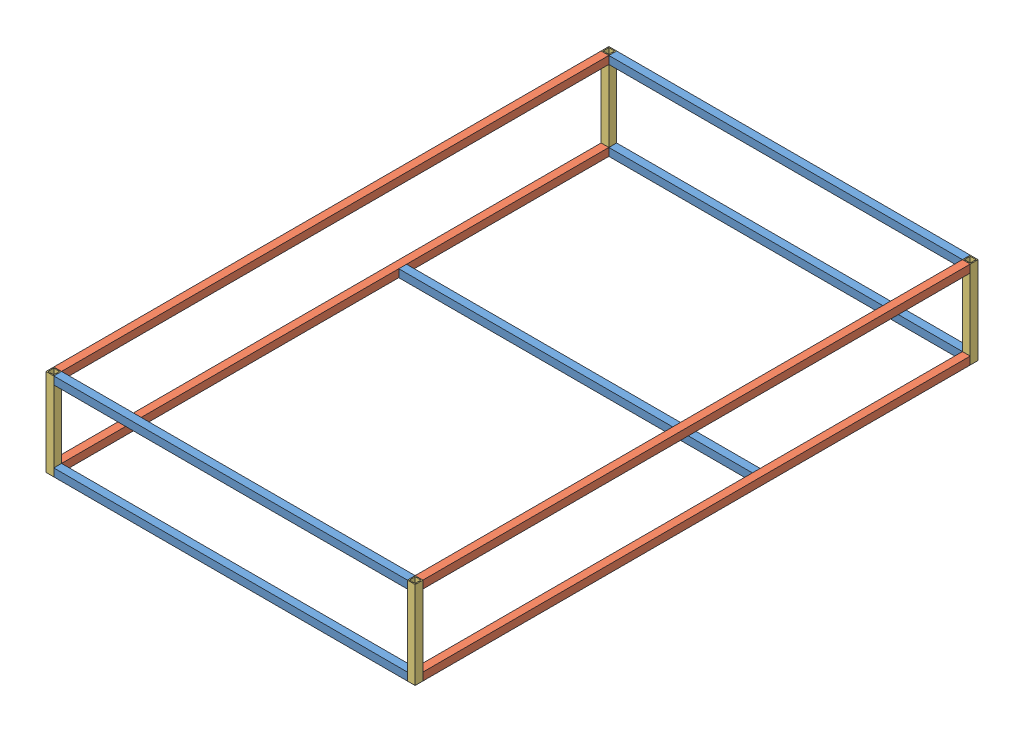
SolidWorks assembly Frame (Base), configuration Default. Lengths in mm.
Overall size (1900 450 2897).
13 component instances, 3 part files, 31 mates.
Components (placement in the parent):
- Frame 1820 steel extrusion-8: Frame 1820 steel extrusion [Default] at origin size (1820 40 40)
- Frame 1820 steel extrusion-9: Frame 1820 steel extrusion [Default] at (0 0 -1775.6695) x (1 0 0) z (0 1 0) size (1820 40 40)
- Frame 1820 steel extrusion-10: Frame 1820 steel extrusion [Default] at (0 410 0) size (1820 40 40)
- Frame 1820 steel extrusion-12: Frame 1820 steel extrusion [Default] at (0 0 -2857) x (1 0 0) z (0 0 -1) size (1820 40 40)
- Frame 1820 steel extrusion-13: Frame 1820 steel extrusion [Default] at (0 410 -2857) x (1 0 0) z (0 1 0) size (1820 40 40)
- Frame 2857 steel extrusion-1: Frame 2857 steel extrusion [Default] at (930 0 -1428.5) x (0 1 0) z (-1 0 0) size (40 2817 40)
- Frame 2857 steel extrusion-2: Frame 2857 steel extrusion [Default] at (930 410 -1428.5) x (0 1 0) z (-1 0 0) size (40 2817 40)
- Frame 2857 steel extrusion-3: Frame 2857 steel extrusion [Default] at (-930 410 -1428.5) x (0 1 0) z (-1 0 0) size (40 2817 40)
- Frame 2857 steel extrusion-4: Frame 2857 steel extrusion [Default] at (-930 0 -1428.5) x (0 1 0) z (-1 0 0) size (40 2817 40)
- Frame 450 steel extrusion-1: Frame 450 steel extrusion [Default] at (-930 205 0) x (0 0 -1) z (-1 0 0) size (40 450 40)
- Frame 450 steel extrusion-2: Frame 450 steel extrusion [Default] at (930 205 0) x (0 0 -1) z (-1 0 0) size (40 450 40)
- Frame 450 steel extrusion-3: Frame 450 steel extrusion [Default] at (930 205 -2857) x (0 0 -1) z (-1 0 0) size (40 450 40)
- Frame 450 steel extrusion-4: Frame 450 steel extrusion [Default] at (-930 205 -2857) x (1 0 0) z (0 0 -1) size (40 450 40)
Mates (geometry in assembly coordinates):
- Coincidente129: coincident: line of assembly; line of assembly; line of Frame 2857 steel extrusion-1 through (910 -20 -20) axis (0 1 0); line of Frame 450 steel extrusion-2 through (910 -20 -20) axis (0 1 0)
- Coincidente130: coincident: line of assembly; line of assembly; line of Frame 2857 steel extrusion-1 through (950 -20 -20) axis (-1 0 0); line of Frame 450 steel extrusion-2 through (910 -20 -20) axis (1 0 0)
- Coincidente133: coincident: line of assembly; line of assembly; line of Frame 2857 steel extrusion-1 through (910 20 -2837) axis (0 0 1); line of Frame 1820 steel extrusion-9 through (910 20 -1795.6695) axis (0 0 1)
- Coincidente171: coincident: line of assembly; line of assembly; line of Frame 2857 steel extrusion-1 through (950 20 -2837) axis (0 -1 0); line of Frame 450 steel extrusion-3 through (950 -20 -2837) axis (0 1 0)
- Coincidente116: coincident: line of assembly; line of assembly; line of Frame 450 steel extrusion-1 through (-910 -20 20) axis (0 1 0); line of Frame 1820 steel extrusion-10 through (-910 430 20) axis (0 -1 0)
- Coincidente117: coincident: line of assembly; line of assembly; line of Frame 450 steel extrusion-1 through (-910 430 20) axis (-1 0 0); line of Frame 1820 steel extrusion-10 through (910 430 20) axis (-1 0 0)
- Coincidente139: coincident: line of assembly; line of assembly; line of Frame 450 steel extrusion-1 through (-950 -20 -20) axis (0 1 0); line of Frame 2857 steel extrusion-3 through (-950 390 -20) axis (0 1 0)
- Coincidente140: coincident: line of assembly; line of assembly; line of Frame 450 steel extrusion-1 through (-950 430 -20) axis (1 0 0); line of Frame 2857 steel extrusion-3 through (-950 430 -20) axis (1 0 0)
- Coincidente180: coincident: line of assembly; line of assembly; line of Frame 450 steel extrusion-1 through (-950 -20 -20) axis (1 0 0); line of Frame 2857 steel extrusion-4 through (-910 -20 -20) axis (-1 0 0)
- Coincidente127: coincident: plane of assembly; plane of assembly; plane of Frame 450 steel extrusion-2 through (950 -20 -20) normal (1 0 0); plane of Frame 450 steel extrusion-3 through (950 -20 -2877) normal (1 0 0)
- Coincidente137: coincident: line of assembly; line of assembly; line of Frame 450 steel extrusion-2 through (950 -20 -20) axis (0 1 0); line of Frame 2857 steel extrusion-2 through (950 430 -20) axis (0 -1 0)
- Coincidente138: coincident: line of assembly; line of assembly; line of Frame 450 steel extrusion-2 through (910 430 -20) axis (1 0 0); line of Frame 2857 steel extrusion-2 through (910 430 -20) axis (1 0 0)
- Coincident15: coincident: plane of assembly; plane of assembly; plane of Frame 450 steel extrusion-3 through (910 -20 -2877) normal (-1 0 0); plane of Frame 1820 steel extrusion-13 through (910 410 -2857) normal (1 0 0)
- Coincident16: coincident: plane of assembly; plane of assembly; plane of Frame 450 steel extrusion-3 through (930 430 -2857) normal (0 1 0); plane of Frame 1820 steel extrusion-13 through (910 430 -2837) normal (0 1 0)
- Coincident17: coincident: plane of assembly; plane of assembly; plane of Frame 450 steel extrusion-3 through (910 -20 -2837) normal (0 0 1); plane of Frame 1820 steel extrusion-13 through (910 430 -2837) normal (0 0 1)
- Coincident18: coincident: plane of assembly; plane of assembly; plane of Frame 450 steel extrusion-3 through (930 430 -2857) normal (0 1 0); plane of Frame 2857 steel extrusion-2 through (910 430 -2837) normal (0 1 0)
- Coincident19: coincident: plane of assembly; plane of assembly; plane of Frame 1820 steel extrusion-13 through (910 430 -2837) normal (0 1 0); plane of Frame 450 steel extrusion-4 through (-930 430 -2857) normal (0 1 0)
- Coincident21: coincident: plane of assembly; plane of assembly; plane of Frame 1820 steel extrusion-13 through (910 430 -2837) normal (0 1 0); plane of Frame 2857 steel extrusion-3 through (-950 430 -2837) normal (0 1 0)
- Coincident22: coincident: plane of assembly; plane of assembly; plane of Frame 450 steel extrusion-2 through (910 -20 -20) normal (-1 0 0); plane of Frame 1820 steel extrusion-10 through (910 410 0) normal (1 0 0)
- Coincident23: coincident: plane of assembly; plane of assembly; plane of Frame 450 steel extrusion-2 through (910 -20 20) normal (0 0 1); plane of Frame 1820 steel extrusion-10 through (910 390 20) normal (0 0 1)
- Coincident24: coincident: plane of assembly; plane of assembly; plane of Frame 450 steel extrusion-1 through (-950 -20 -20) normal (-1 0 0); plane of Frame 2857 steel extrusion-4 through (-950 20 -2837) normal (-1 0 0)
- Coincident25: coincident: plane of assembly; plane of assembly; plane of Frame 1820 steel extrusion-13 through (910 430 -2837) normal (0 0 1); plane of Frame 450 steel extrusion-4 through (-910 -20 -2837) normal (0 0 1)
- Coincident26: coincident: plane of assembly; plane of assembly; plane of Frame 450 steel extrusion-4 through (-950 -20 -2877) normal (-1 0 0); plane of Frame 2857 steel extrusion-4 through (-950 20 -2837) normal (-1 0 0)
- Coincident29: coincident: plane of assembly; plane of assembly; plane of Frame 450 steel extrusion-1 through (-930 -20 0) normal (0 -1 0); plane of Frame 2857 steel extrusion-4 through (-950 -20 -2837) normal (0 -1 0)
- Coincident30: coincident: plane of assembly; plane of assembly; plane of Frame 450 steel extrusion-1 through (-950 -20 20) normal (0 0 1); plane of Frame 1820 steel extrusion-8 through (910 -20 20) normal (0 0 1)
- Coincident33: coincident: plane of assembly; plane of assembly; plane of Frame 2857 steel extrusion-4 through (-950 -20 -2837) normal (0 -1 0); plane of Frame 1820 steel extrusion-8 through (910 -20 20) normal (0 -1 0)
- Coincident34: coincident: plane of assembly; plane of assembly; plane of Frame 450 steel extrusion-1 through (-910 -20 -20) normal (1 0 0); plane of Frame 1820 steel extrusion-8 through (-910 0 0) normal (-1 0 0)
- Coincident35: coincident: plane of assembly; plane of assembly; plane of Frame 1820 steel extrusion-12 through (-910 0 -2857) normal (-1 0 0); plane of Frame 450 steel extrusion-4 through (-910 -20 -2877) normal (1 0 0)
- Coincident36: coincident: plane of assembly; plane of assembly; plane of Frame 1820 steel extrusion-12 through (910 -20 -2877) normal (0 -1 0); plane of Frame 2857 steel extrusion-4 through (-950 -20 -2837) normal (0 -1 0)
- Coincident37: coincident: plane of assembly; plane of assembly; plane of Frame 1820 steel extrusion-12 through (910 20 -2877) normal (0 0 -1); plane of Frame 450 steel extrusion-4 through (-910 -20 -2877) normal (0 0 -1)
- Coincident38: coincident: plane of assembly; plane of assembly; plane of Frame 1820 steel extrusion-9 through (910 20 -1755.6695) normal (0 1 0); plane of Frame 2857 steel extrusion-4 through (-950 20 -2837) normal (0 1 0)
